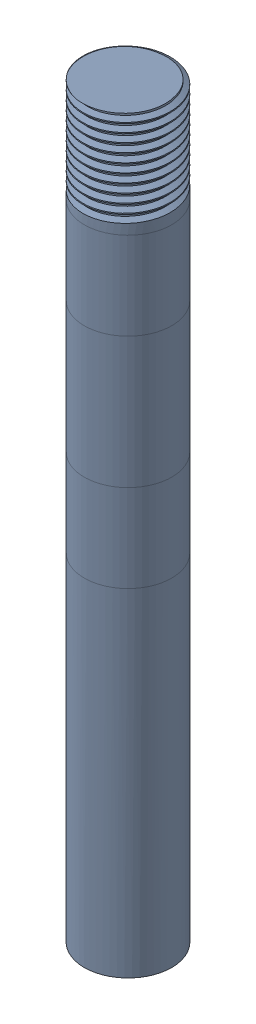
SolidWorks assembly Differential Frame Connection, configuration Default. Lengths in mm.
Overall size (15.05 109.05 15.28).
7 component instances, 5 part files, 14 mates.
Components (placement in the parent):
- Shaft-1: Shaft [Default] at (0 42.2683 0) x (0 -1 0) z (0.194107 0 -0.98098) size (109.05 12.76 13.05)
- 4520N279_Ready-Mount Bearing Housing with Two-Bolt Flange-1: 4520N279_Ready-Mount Bearing Housing with Two-Bolt Flange [4520N279] x (-1 0 0) z (0 -1 0) (suppressed, hidden)
- 6384K361_Ball Bearing-1: 6384K361_Ball Bearing [6384K361] at (0 -12.7 0) x (0.878371 0 -0.47798) z (0 1 0) (suppressed, hidden)
- Base-1: Base [Default] at origin (suppressed, hidden)
- 4520N279_Ready-Mount Bearing Housing with Two-Bolt Flange-3: 4520N279_Ready-Mount Bearing Housing with Two-Bolt Flange [4520N279] at (0 6.35 0) x (-1 0 0) z (0 1 0) (suppressed, hidden)
- 6384K361_Ball Bearing-2: 6384K361_Ball Bearing [6384K361] at (0 19.05 0) x (-0.997671 0 -0.068215) z (0 -1 0) (suppressed, hidden)
- 92673A141_18-8 Stainless Steel Hex Nut-1: 92673A141_18-8 Stainless Steel Hex Nut [92673A141] at (0 30.9563 0) x (0.154076 0 0.988059) z (0 1 0) (suppressed, hidden)
Mates (geometry in assembly coordinates):
- Concentric1: concentric aligned: cylinder of 4520N279_Ready-Mount Bearing Housing with Two-Bolt Flange-1 through (0 -7.9375 0) axis (0 1 0) radius 14.2875; cylinder of 6384K361_Ball Bearing-1 through (0 -7.9375 0) axis (0 1 0) radius 14.2875
- Coincident1: coincident anti-aligned: plane of 4520N279_Ready-Mount Bearing Housing with Two-Bolt Flange-1 through (0 -15.875 0) normal (0 -1 0); plane of 6384K361_Ball Bearing-1 through (-6.2338 -15.875 -11.4556) normal (0 1 0)
- Concentric2: concentric aligned: cylinder of Shaft-1 through (0 358.231 0) axis (0 1 0) radius 6.35; cylinder of 6384K361_Ball Bearing-1 through (0 -7.9375 0) axis (0 1 0) radius 6.35
- Concentric3: concentric anti-aligned: cylinder of 4520N279_Ready-Mount Bearing Housing with Two-Bolt Flange-1 through (39.6875 -7.9375 0) axis (0 1 0) radius 5.1594; cylinder of Base-1 through (39.6875 6.35 0) axis (0 -1 0) radius 2.75
- Concentric4: concentric anti-aligned: cylinder of 4520N279_Ready-Mount Bearing Housing with Two-Bolt Flange-1 through (-39.6875 -7.9375 0) axis (0 1 0) radius 5.1594; cylinder of Base-1 through (-39.6875 6.35 0) axis (0 -1 0) radius 2.75
- Coincident3: coincident anti-aligned: plane of 4520N279_Ready-Mount Bearing Housing with Two-Bolt Flange-1 through (39.6875 0 0) normal (0 1 0); plane of Base-1 through (0 0 0) normal (0 -1 0)
- Coincident4: coordinate: point of Base-1
- Coincident6: coincident anti-aligned: plane of 4520N279_Ready-Mount Bearing Housing with Two-Bolt Flange-3 through (0 22.225 0) normal (0 1 0); plane of 6384K361_Ball Bearing-2 through (0.8897 22.225 -13.0115) normal (0 -1 0)
- Concentric5: concentric aligned: cylinder of 4520N279_Ready-Mount Bearing Housing with Two-Bolt Flange-3 through (0 14.2875 0) axis (0 -1 0) radius 14.2875; cylinder of 6384K361_Ball Bearing-2 through (0 14.2875 0) axis (0 -1 0) radius 14.2875
- Concentric6: concentric anti-aligned: cylinder of Shaft-1 through (0 358.231 0) axis (0 1 0) radius 6.35; cylinder of 6384K361_Ball Bearing-2 through (0 14.2875 0) axis (0 -1 0) radius 6.35
- Coincident7: coincident anti-aligned: plane of Base-1 through (0 6.35 0) normal (0 1 0); plane of 4520N279_Ready-Mount Bearing Housing with Two-Bolt Flange-3 through (39.6875 6.35 0) normal (0 -1 0)
- Concentric7: concentric aligned: cylinder of Base-1 through (39.6875 6.35 0) axis (0 -1 0) radius 2.75; cylinder of 4520N279_Ready-Mount Bearing Housing with Two-Bolt Flange-3 through (39.6875 14.2875 0) axis (0 -1 0) radius 5.1594
- Screw1: screw = 1 aligned: cylinder of Shaft-1 through (0 358.231 0) axis (0 1 0) radius 6.35; circle of 92673A141_18-8 Stainless Steel Hex Nut-1
- LimitDistance1: limit distance = 0 mm anti-aligned: plane of 6384K361_Ball Bearing-2 through (0.4657 25.4 -6.8103) normal (0 1 0); plane of 92673A141_18-8 Stainless Steel Hex Nut-1 through (3.966 25.4001 -10.2586) normal (0 -1 0)
